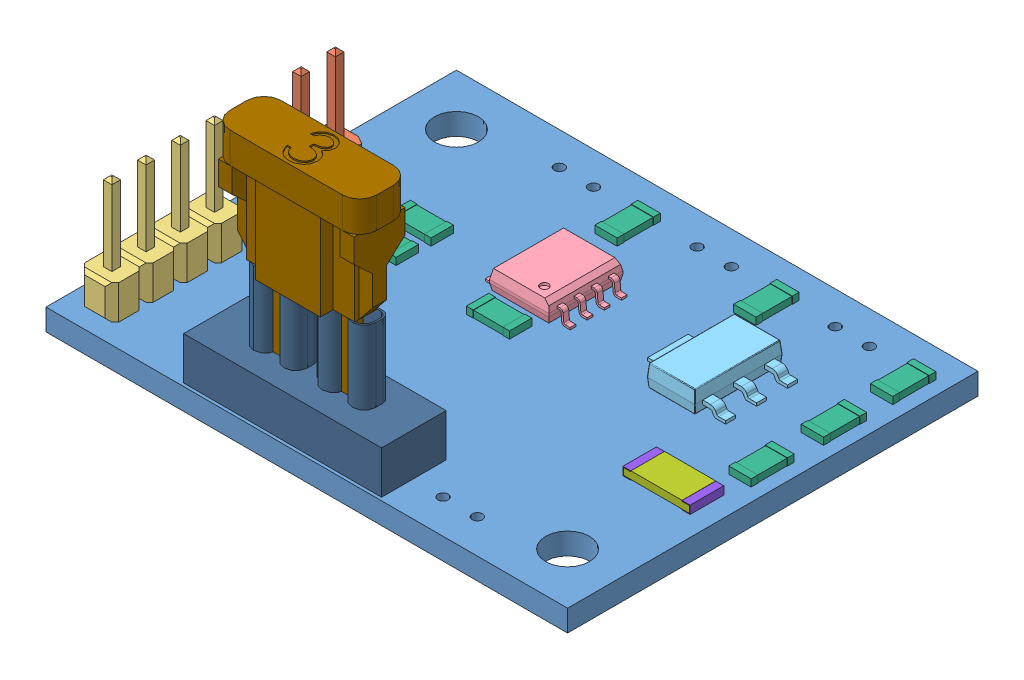
SolidWorks assembly PCB, CHARGE BOARD, configuration Default. Lengths in mm.
Overall size (38.73 21.23 30.48).
19 component instances, 10 part files, 22 mates.
Components (placement in the parent):
- PCB, CHARGE BOARD-1: PCB, CHARGE BOARD [Default] x (1 0 0) z (0 1 0) size (38.73 30.48 1.6)
- HDR1x2_-3: HDR1x2_ [Default] at (-16.8961 3.34 -1.2365) x (0 0 -1) z (-1 0 0) size (5.08 12.19 2.54)
- HDR1x4-1: HDR1x4 [Default] at (-16.966 0.8 12.7485) x (0 0 -1) z (1 0 0) size (10.16 12.19 2.54)
- SO_IC8-1: SO_IC8 [Default] at (-1.5846 1.7 -4.8651) x (0 0 1) z (-1 0 0) size (5.5 1.6 6.3)
- SOT-223-1: SOT-223 [Default] at (9.921 1.5 -5.1354) x (0 0 1) z (-1 0 0) size (6.5 1.68 6.96)
- Resistor 1206-4: Resistor 1206 [Default] at (-1.6904 1.3 -0.7338) x (1 0 0) z (0 0 -1) size (3.2 0.56 1.66)
- Resistor 1206-5: Resistor 1206 [Default] at (-10.6337 1.3 -1.2635) x (1 0 0) z (0 0 -1) size (3.2 0.56 1.66)
- Resistor 1206-6: Resistor 1206 [Default] at (-10.5857 1.3 -3.8039) x (1 0 0) z (0 0 -1) size (3.2 0.56 1.66)
- Resistor 1206-7: Resistor 1206 [Default] at (17.5234 1.3 -11.5247) x (0 0 -1) z (-1 0 0) size (3.2 0.56 1.66)
- Resistor 1206-9: Resistor 1206 [Default] at (-2.8991 1.3 -11.4814) x (0 0 -1) z (-1 0 0) size (3.2 0.56 1.66)
- Resistor 1206-10: Resistor 1206 [Default] at (17.5646 1.3 -0.9643) x (0 0 -1) z (-1 0 0) size (3.2 0.56 1.66)
- Resistor 1206-12: Resistor 1206 [Default] at (7.3429 1.3 -11.5481) x (0 0 -1) z (-1 0 0) size (3.2 0.56 1.66)
- User Library-RES_2010L-1: User Library-RES_2010L [Default] at (15.3929 1.1 3.4133) size (5 0.61 2.5)
  - User Library-RES_2010L_RES_2010_Body_1-1: User Library-RES_2010L_RES_2010_Body_1 [Default] at origin size (4.9 0.56 2.5)
  - User Library-RES_2010L_RES_2010_Lead_1-1: User Library-RES_2010L_RES_2010_Lead_1 [Default] at origin size (0.6 0.6 2.5)
  - User Library-RES_2010L_RES_2010_Lead_1-2: User Library-RES_2010L_RES_2010_Lead_1 [Default] x (-1 0 0) z (0 0 -1) size (0.6 0.6 2.5)
- Mini blade fuse - 1 to 40 a - 32 v-1: Mini blade fuse - 1 to 40 a - 32 v [3 A] at (-7.7757 15.9356 14.4425) x (1 0 0) z (0 1 0) size (10.9 3.81 16.3)
- Mini Blade Fuse Holder, PCB-1: Mini Blade Fuse Holder, PCB [Default] at (-2.027 0.8 12.6144) size (14.7 8.64 4.8)
- Resistor 1206-14: Resistor 1206 [Default] at (17.5733 1.3 -6.3368) x (0 0 -1) z (-1 0 0) size (3.2 0.56 1.66)
Mates (geometry in assembly coordinates):
- Coincident2: coincident anti-aligned: plane of PCB, CHARGE BOARD-1 through (19.3675 0.8 -15.24) normal (0 1 0); plane of SOT-223-1 through (8.141 0.8 -8.3854) normal (0 -1 0)
- Coincident3: coincident anti-aligned: plane of PCB, CHARGE BOARD-1 through (19.3675 0.8 -15.24) normal (0 1 0); plane of SO_IC8-1 through (-4.1346 0.8 -6.5601) normal (0 -1 0)
- Parallel1: parallel anti-aligned: line of SOT-223-1 through (8.141 1.5 -3.6354) axis (0 0 1); line of PCB, CHARGE BOARD-1 through (19.3675 0.8 15.24) axis (0 0 -1)
- Parallel4: parallel aligned: line of PCB, CHARGE BOARD-1 through (-19.3675 0.8 15.24) axis (1 0 0); line of SO_IC8-1 through (-3.7846 1.7 -2.1151) axis (1 0 0)
- Coincident6: coincident anti-aligned: plane of PCB, CHARGE BOARD-1 through (19.3675 0.8 -15.24) normal (0 1 0); plane of HDR1x2_-3 through (-18.1661 0.8 0.0335) normal (0 -1 0)
- Parallel5: parallel anti-aligned: plane of PCB, CHARGE BOARD-1 through (-19.3675 0.8 15.24) normal (-1 0 0); plane of HDR1x2_-3 through (-15.6261 0.8 0.0335) normal (1 0 0)
- Coincident12: coincident anti-aligned: plane of PCB, CHARGE BOARD-1 through (19.3675 0.8 -15.24) normal (0 1 0); plane of HDR1x4-1 through (-15.696 0.8 14.0185) normal (0 -1 0)
- Coincident161: coincident anti-aligned: plane of PCB, CHARGE BOARD-1 through (19.3675 0.8 -15.24) normal (0 1 0); plane of Resistor 1206-4 through (-3.2904 0.8 -1.5338) normal (0 -1 0)
- Coincident171: coincident anti-aligned: plane of PCB, CHARGE BOARD-1 through (19.3675 0.8 -15.24) normal (0 1 0); plane of Resistor 1206-5 through (-12.2337 0.8 -2.0635) normal (0 -1 0)
- Coincident181: coincident anti-aligned: plane of PCB, CHARGE BOARD-1 through (19.3675 0.8 -15.24) normal (0 1 0); plane of Resistor 1206-6 through (-12.1857 0.8 -4.6039) normal (0 -1 0)
- Coincident191: coincident anti-aligned: plane of PCB, CHARGE BOARD-1 through (19.3675 0.8 -15.24) normal (0 1 0); plane of Resistor 1206-7 through (16.7234 0.8 -9.9247) normal (0 -1 0)
- Parallel7: parallel anti-aligned: line of PCB, CHARGE BOARD-1 through (19.3675 0.8 15.24) axis (0 0 -1); line of Resistor 1206-7 through (18.3234 1.3 -12.6247) axis (0 0 1)
- Coincident211: coincident anti-aligned: plane of PCB, CHARGE BOARD-1 through (19.3675 0.8 -15.24) normal (0 1 0); plane of Resistor 1206-9 through (-3.6991 0.8 -9.8814) normal (0 -1 0)
- Coincident221: coincident anti-aligned: plane of PCB, CHARGE BOARD-1 through (19.3675 0.8 -15.24) normal (0 1 0); plane of Resistor 1206-10 through (16.7646 0.8 0.6357) normal (0 -1 0)
- Coincident241: coincident anti-aligned: plane of PCB, CHARGE BOARD-1 through (19.3675 0.8 -15.24) normal (0 1 0); plane of Resistor 1206-12 through (6.5429 0.8 -9.9481) normal (0 -1 0)
- Coincident242: coincident anti-aligned: plane of PCB, CHARGE BOARD-1 through (19.3675 0.8 -15.24) normal (0 1 0); plane of User Library-RES_2010L-1/User Library-RES_2010L_RES_2010_Lead_1-1 through (17.5929 0.8 2.1633) normal (0 -1 0)
- Coincident244: coincident anti-aligned: plane of PCB, CHARGE BOARD-1 through (19.3675 0.8 -15.24) normal (0 1 0); plane of Mini Blade Fuse Holder, PCB-1 through (5.323 0.8 10.2144) normal (0 -1 0)
- Coincident245: coincident aligned: plane of PCB, CHARGE BOARD-1 through (0 0 0) normal (0 1 0); plane of assembly through (0 0 0) normal (0 1 0)
- Coincident246: coincident aligned: plane of PCB, CHARGE BOARD-1; plane of assembly through (0 0 0) normal (1 0 0)
- Coincident247: coincident anti-aligned: plane of PCB, CHARGE BOARD-1 through (0 0 0) normal (0 0 -1); plane of assembly through (0 0 0) normal (0 0 1)
- Coincident2491: coincident anti-aligned: plane of PCB, CHARGE BOARD-1 through (19.3675 0.8 -15.24) normal (0 1 0); plane of Resistor 1206-14 through (16.7733 0.8 -4.7368) normal (0 -1 0)
- Parallel8: parallel aligned: plane of PCB, CHARGE BOARD-1 through (-19.3675 0.8 15.24) normal (0 0 1); plane of Mini blade fuse - 1 to 40 a - 32 v-1 through (1.1743 1.9216 12.86) normal (0 0 1)
